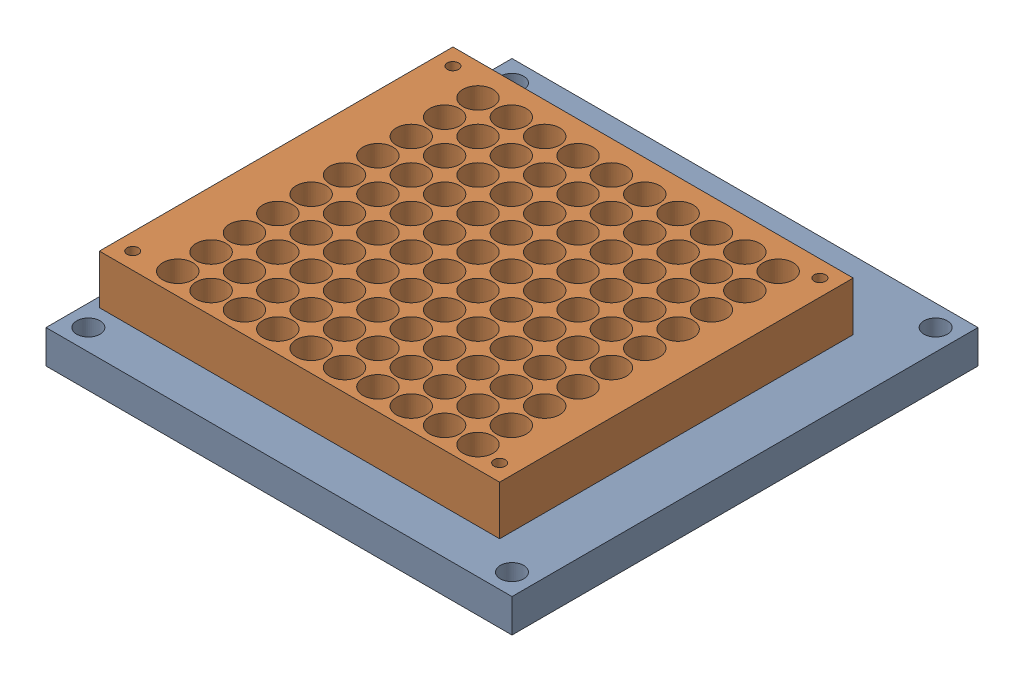
SolidWorks assembly TestingSetup, configuration Default. Lengths in mm.
Overall size (139.7 24.7 139.7).
3 component instances, 3 part files, 6 mates.
Components (placement in the parent):
- BottomHousing_10x10-1: BottomHousing_10x10 [Default] at (-33.5 18.2428 55.2836) size (139.7 10 139.7)
- MagnetShielding-1: MagnetShielding [Default] at (89.35 42.9428 42.1368) x (-1 0 0) z (0 0 1) size (120 14.7 106)
- PCB_LargeInductor-1: PCB_LargeInductor [Default] at (48.6 26.6428 -17.8632) x (-1 0 0) z (0 0 -1) size (20.5 1.57 30)
Mates (geometry in assembly coordinates):
- Coincident1: coincident: plane of BottomHousing_10x10-1 through (-33.5 26.6428 55.2836) normal (0 1 0); plane of PCB_LargeInductor-1 through (49.021 28.2428 -17.6384) normal (0 -1 0)
- Parallel1: parallel: line of BottomHousing_10x10-1 through (49.1 28.2428 -18.3632) axis (-1 0 0); line of PCB_LargeInductor-1 through (49.021 29.8128 -17.6384) axis (-1 0 0)
- Coincident4: coincident anti-aligned: plane of BottomHousing_10x10-1 through (-33.5 28.2428 55.2836) normal (0 1 0); plane of MagnetShielding-1 through (89.35 28.2428 42.1368) normal (0 -1 0)
- Concentric2: concentric aligned: circle of BottomHousing_10x10-1; circle of MagnetShielding-1
- Concentric3: concentric aligned: circle of BottomHousing_10x10-1; circle of MagnetShielding-1
- Concentric4: concentric anti-aligned: circle of MagnetShielding-1; circle of PCB_LargeInductor-1
